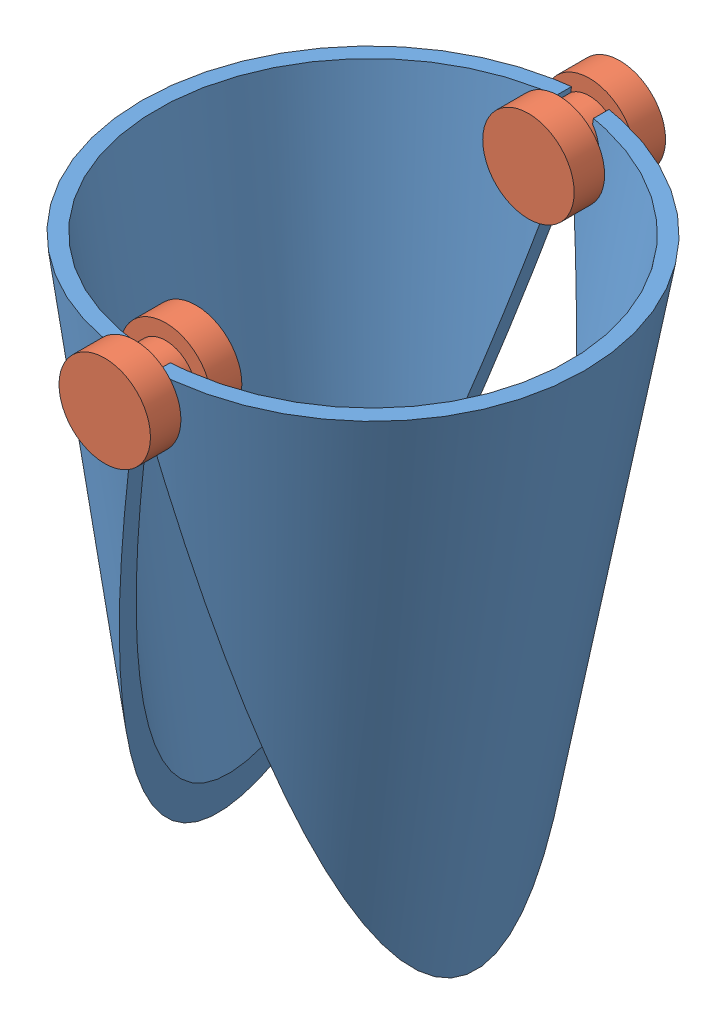
SolidWorks assembly Assem2, configuration Default. Lengths in mm.
Overall size (92.29 126.46 107.35).
4 component instances, 2 part files, 6 mates.
Components (placement in the parent):
- Claw 3-1: Claw 3 [Default] at (-40.3712 -11.7944 -19.6339) size (44.77 120.65 95.13)
- Claw 3-2: Claw 3 [Default] at (-43.2521 -11.7126 -19.6339) x (-0.998388 0.056755 0) z (0 0 -1) size (44.77 120.65 95.13)
- Claw Pin 2-1: Claw Pin 2 [Default] at (-41.9872 -17.9354 21.34) size (19.05 19.05 19.05)
- Claw Pin 2-2: Claw Pin 2 [Default] at (-41.9872 -17.9354 -66.9577) size (19.05 19.05 19.05)
Mates (geometry in assembly coordinates):
- Concentric1: concentric aligned: cylinder of Claw 3-2 through (-41.9872 -17.9354 27.9911) axis (0 0 -1) radius 6.35; cylinder of Claw Pin 2-2 through (-41.9872 -17.9354 -60.6077) axis (0 0 -1) radius 6.35
- Distance1: distance = 0 mm: point of Claw 3-2; plane of Claw Pin 2-2 through (-41.9872 -17.9354 -66.9577) normal (0 0 1)
- Concentric2: concentric aligned: cylinder of Claw 3-2 through (-41.9872 -17.9354 27.9911) axis (0 0 -1) radius 6.35; cylinder of Claw Pin 2-1 through (-41.9872 -17.9354 27.69) axis (0 0 -1) radius 6.35
- Coincident3: coincident: point of Claw 3-2; plane of Claw Pin 2-1 through (-41.9872 -17.9354 27.69) normal (0 0 -1)
- Concentric3: concentric anti-aligned: cylinder of Claw 3-1 through (-41.9872 -17.9354 -67.2589) axis (0 0 1) radius 6.35; cylinder of Claw Pin 2-1 through (-41.9872 -17.9354 27.69) axis (0 0 -1) radius 6.35
- Coincident4: coincident: point of Claw 3-1; plane of Claw Pin 2-2 through (-41.9872 -17.9354 -66.9577) normal (0 0 1)
